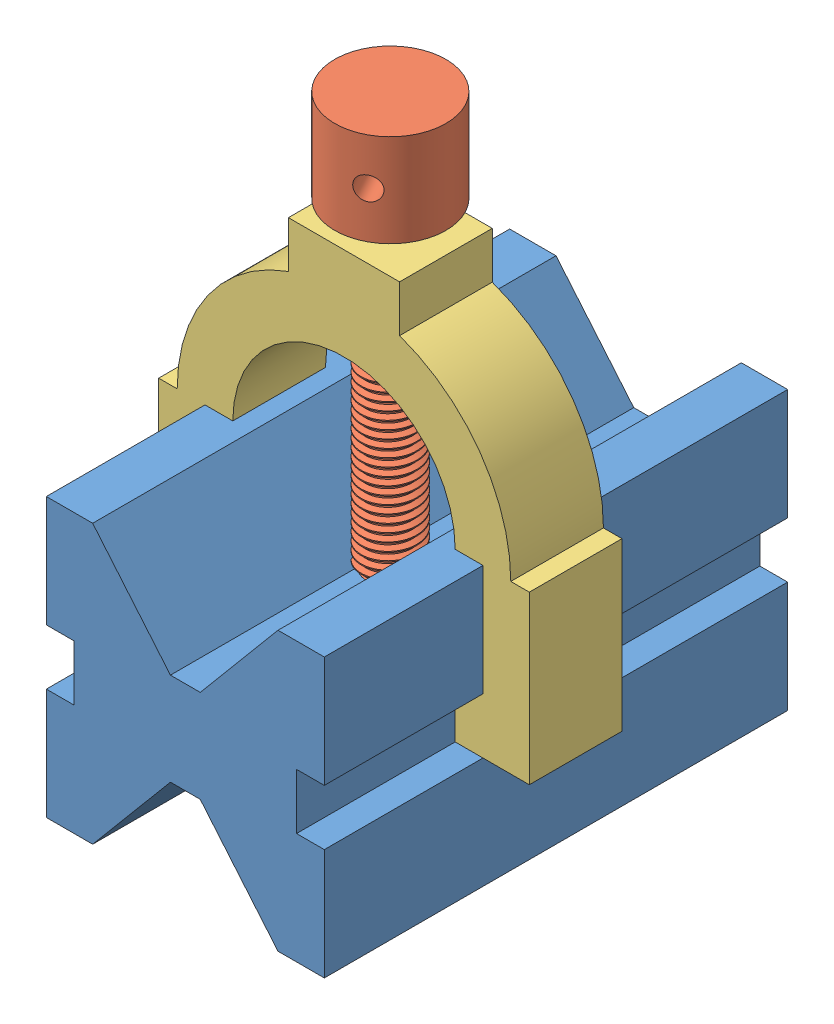
SolidWorks assembly Pipe Vice, configuration Default. Lengths in mm.
Overall size (80 128.6 100).
3 component instances, 3 part files, 3 mates.
Components (placement in the parent):
- Base-1: Base [Default] at (42.0386 56.4229 21.3936) size (60 60 100)
- Rode-1: Rode [Default] at (42.0386 155.0229 77.1517) x (-0.879297 0 0.476273) z (-0.476273 0 -0.879297) size (24 101.01 24)
- Slider-1: Slider [Default] at (42.0386 86.4229 67.1517) size (80 80.67 20)
Mates (geometry in assembly coordinates):
- Coincident9: coincident anti-aligned: plane of Base-1 through (66.0386 62.4229 121.3936) normal (1 0 0); plane of Slider-1 through (66.0386 50.4229 87.1517) normal (-1 0 0)
- Coincident10: coincident anti-aligned: plane of Base-1 through (66.0386 50.4229 121.3936) normal (0 1 0); plane of Slider-1 through (82.0386 50.4229 87.1517) normal (0 -1 0)
- Concentric2: concentric aligned: cylinder of Rode-1 through (42.0386 135.0229 77.1517) axis (0 1 0) radius 12; cylinder of Slider-1 through (42.0386 80.4229 77.1517) axis (0 1 0) radius 6
